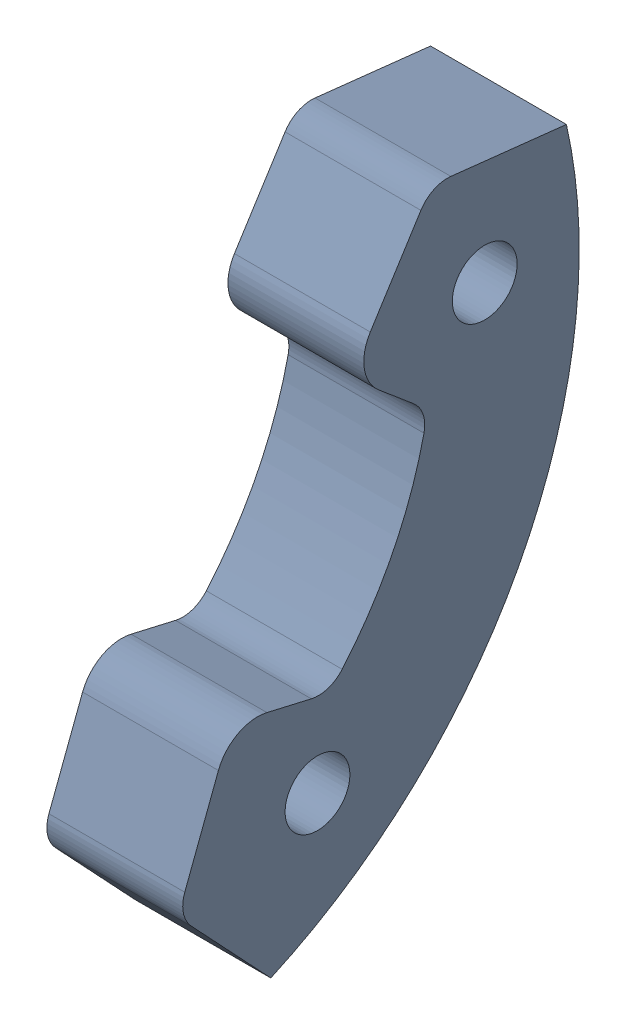
SolidWorks assembly MFG CW Left Brake Limiter Asmbly, configuration Default. Lengths in mm.
Overall size (13 57.83 37.94).
3 component instances, 2 part files, 0 mates.
Components (placement in the parent):
- MFG CW Left Brake Limiter-1: MFG CW Left Brake Limiter [Default] x (-1 0 0) z (0 0 -1) size (13 57.83 37.94)
- M6 x 1 Hex Nut-1: M6 x 1 Hex Nut [Default] at (-127.5 76.4725 72.1408) x (0 0.241922 -0.970296) z (-1 0 0) size (10 11.55 5)
- M6 x 1 Hex Nut-2: M6 x 1 Hex Nut [Default] at (-127.5 110.7884 56.139) x (0 0.406737 -0.913545) z (1 0 0) size (10 11.55 5)
